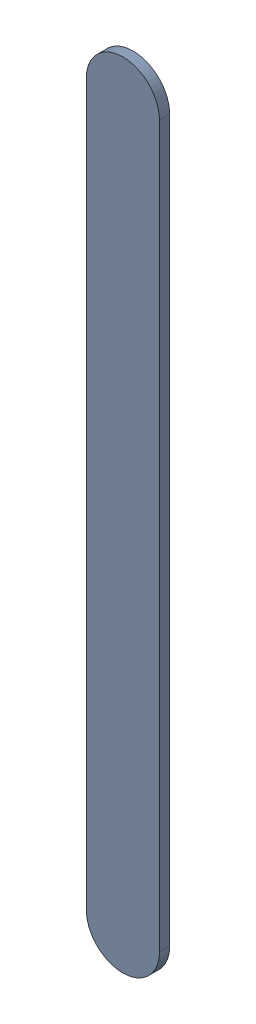
SolidWorks assembly Track (27.19mm,46mm)(27.19mm,48.5mm) on Top Layer, configuration Predeterminado. Lengths in mm.
Overall size (0.25 2.75 0.04).
2 component instances, 1 part files, 0 mates.
Components (placement in the parent):
- Track (27.19mm,46mm)(27.19mm,48.5mm) on Top Layer-1-1: Track (27.19mm,46mm)(27.19mm,48.5mm) on Top Layer-1 [Predeterminado] at (-68.317 -44.187 -0.0457) size (0.25 2.75 0.04)
  - Track (27.19mm,46mm)(27.19mm,48.5mm) on Top Layer-Part-1-1: Track (27.19mm,46mm)(27.19mm,48.5mm) on Top Layer-Part-1 [Predeterminado] at origin size (0.25 2.75 0.04)
